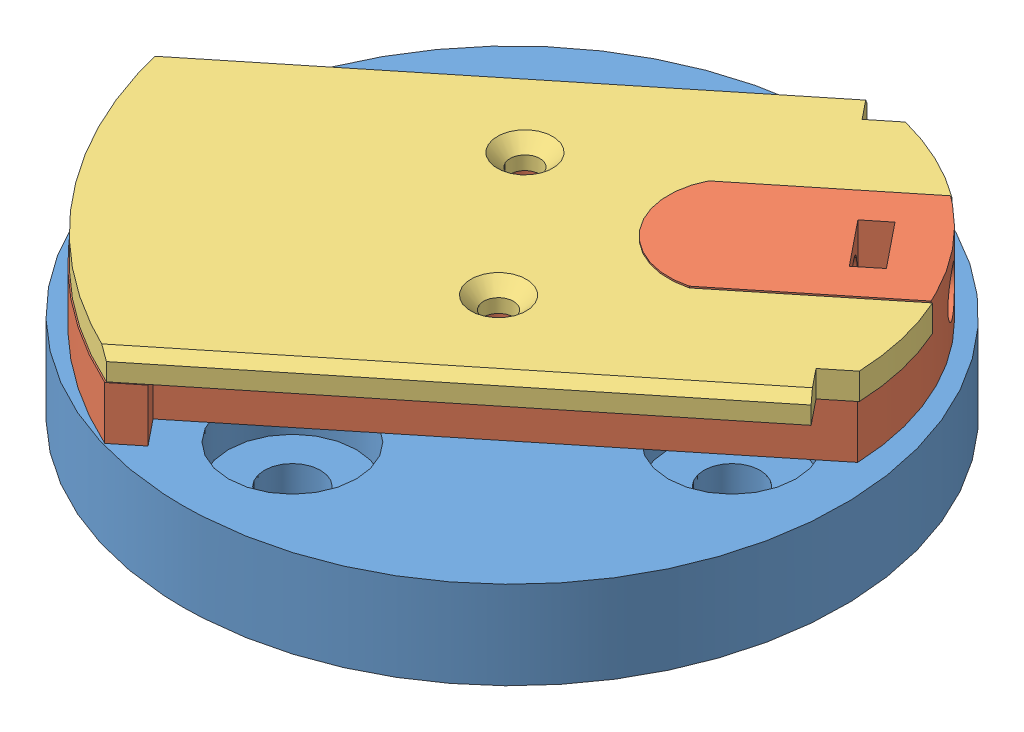
SolidWorks assembly Panda Robot Adaptor Plate + Right Hand Adaptor Assembly, configuration Default. Lengths in mm.
Overall size (82.18 19.17 77.85).
3 component instances, 3 part files, 6 mates.
Components (placement in the parent):
- Panda Robot Adaptor Plate-1: Panda Robot Adaptor Plate [Default] at (-8.2147 -3.806 3.5236) size (75 10 75)
- Right Hand Adaptor Part 2-1: Right Hand Adaptor Part 2 [Default] at (-9.9164 6.194 4.8966) x (0.62795 0 0.778254) z (-0.778254 0 0.62795) size (42.5 9.18 71.3)
- Right Hand Adaptor Part 1-2: Right Hand Adaptor Part 1 [Default] at (-9.8195 12.194 4.8184) x (0.62795 0 0.778254) z (-0.778254 0 0.62795) size (42.3 3 71.05)
Mates (geometry in assembly coordinates):
- Coincident1: coincident anti-aligned: plane of Panda Robot Adaptor Plate-1 through (-8.2147 6.194 3.5236) normal (0 1 0); plane of Right Hand Adaptor Part 2-1 through (-9.9164 6.194 4.8966) normal (0 -1 0)
- Concentric1: concentric aligned: circle of Panda Robot Adaptor Plate-1; circle of Right Hand Adaptor Part 2-1
- Concentric2: concentric aligned: circle of Panda Robot Adaptor Plate-1; circle of Right Hand Adaptor Part 2-1
- Coincident3: coincident anti-aligned: plane of Right Hand Adaptor Part 2-1 through (-9.9164 12.194 4.8966) normal (0 1 0); plane of Right Hand Adaptor Part 1-2 through (-9.8195 12.194 4.8184) normal (0 -1 0)
- Concentric5: concentric aligned: circle of Right Hand Adaptor Part 2-1; circle of Right Hand Adaptor Part 1-2
- Concentric6: concentric aligned: circle of Right Hand Adaptor Part 2-1; circle of Right Hand Adaptor Part 1-2
